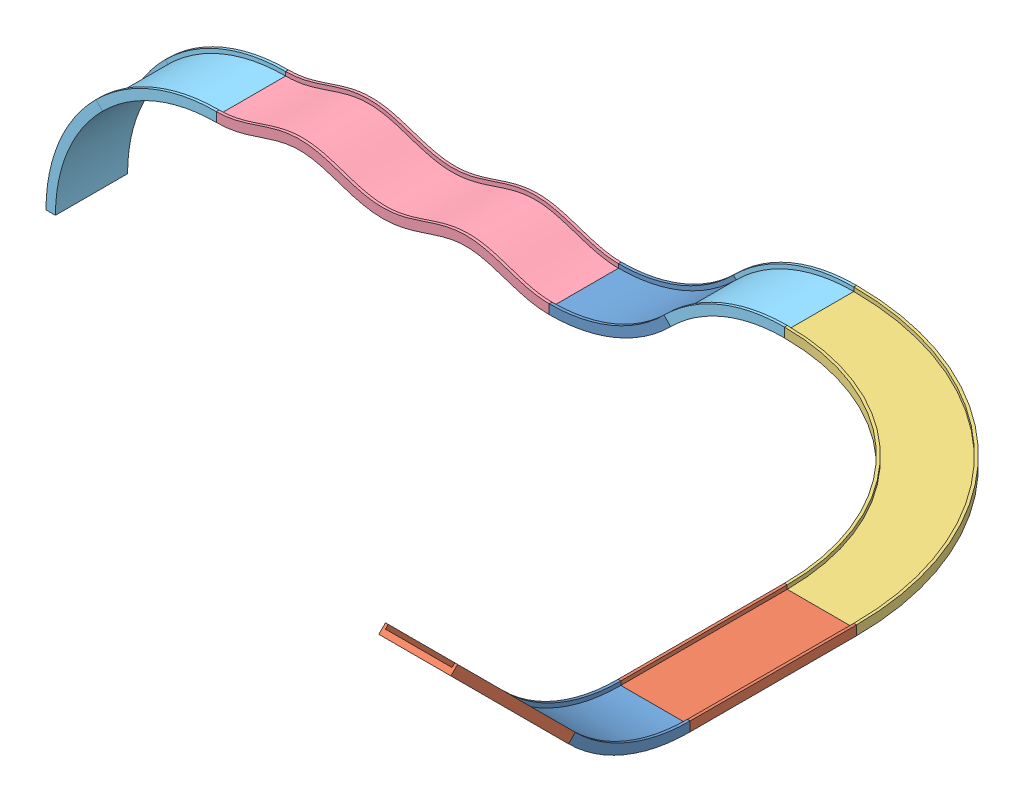
SolidWorks assembly track_js2427, configuration Default. Lengths in mm.
Overall size (9624.51 3946.21 6306.68).
9 component instances, 5 part files, 24 mates.
Components (placement in the parent):
- track_45-0_js2427-1: track_45-0_js2427 [Default] at (322.1788 1336.9708 331.0608) x (-1 0 0) z (0 0 -1) size (650 514.26 1096.02)
- track_straight_js2427-1: track_straight_js2427 [Default] at (322.1788 1336.9708 331.0608) x (-1 0 0) z (0 0 -1) size (650 85.24 1500)
- track_turn90_js2427-1: track_turn90_js2427 [Default] at (-327.8212 1336.9708 -1168.9392) size (2650 85.24 2650)
- track_waves_js2427-1: track_waves_js2427 [Default] at (-7449.1415 458.2911 -3818.9392) x (0 0 1) z (-1 0 0) size (650 244.39 3000.1)
- track_0-45_js2427-1: track_0-45_js2427 [Default] at (-8534.7174 8.6309 -3818.9392) x (0 0 1) z (-0.707107 -0.707107 0) size (650 509.93 1085.58)
- track_0-45_js2427-2: track_0-45_js2427 [Default] at (-7449.1415 458.2911 -3818.9392) x (0 0 1) z (-1 0 0) size (650 509.93 1085.58)
- track_straight_js2427-2: track_straight_js2427 [Default] at (-327.8212 1765.9902 1366.8053) x (1 0 0) z (0 0.707107 0.707107) size (650 85.24 1500)
- track_0-45_js2427-4: track_0-45_js2427 [Default] at (-2327.8212 1336.9708 -3818.9392) x (0 0 1) z (-1 0 0) size (650 509.93 1085.58)
- track_45-0_js2427-3: track_45-0_js2427 [Default] at (-4449.1415 458.2911 -3818.9392) x (0 0 1) z (-1 0 0) size (650 514.26 1096.02)
Mates (geometry in assembly coordinates):
- Coincident4: coincident: plane of track_45-0_js2427-1 through (322.1788 1336.9708 331.0608) normal (0 0 -1); plane of track_straight_js2427-1 through (322.1788 1336.9708 331.0608) normal (0 0 1)
- Coincident5: coincident: plane of track_45-0_js2427-1 through (322.1788 1765.9902 1366.8053) normal (1 0 0); plane of track_straight_js2427-1 through (322.1788 1251.7347 -1168.9392) normal (1 0 0)
- Tangent2: tangent: cylinder of track_45-0_js2427-1 through (322.1788 2801.7347 331.0608) axis (1 0 0) radius 1500; plane of track_straight_js2427-1 through (297.1788 1301.7347 -1168.9392) normal (0 1 0)
- Coincident6: coincident: plane of track_straight_js2427-1 through (322.1788 1336.9708 -1168.9392) normal (0 0 -1); plane of track_turn90_js2427-1 through (-327.8212 1336.9708 -1168.9392) normal (0 0 1)
- Coincident7: coincident: plane of track_straight_js2427-1 through (297.1788 1301.7347 -1168.9392) normal (0 1 0); plane of track_turn90_js2427-1 through (-2327.8212 1301.7347 -3193.9392) normal (0 1 0)
- Tangent3: tangent: plane of track_straight_js2427-1 through (-302.8212 1301.7347 -1168.9392) normal (1 0 0); cylinder of track_turn90_js2427-1 through (-2327.8212 1336.9708 -1168.9392) axis (0 -1 0) radius 2025
- Coincident16: coincident: line of track_0-45_js2427-1 through (-8509.8017 -16.2848 -3793.9392) axis (0 0 1); line of track_0-45_js2427-2 through (-8509.8017 -16.2848 -3793.9392) axis (0 0 1)
- Concentric4: concentric: cylinder of track_0-45_js2427-1 through (-7449.1415 -1076.9449 -3818.9392) axis (0 0 -1) radius 1500; cylinder of track_0-45_js2427-2 through (-7449.1415 -1076.9449 -3818.9392) axis (0 0 -1) radius 1500
- Coincident17: coincident: plane of track_0-45_js2427-1 through (-8899.1415 -1076.9449 -3818.9392) normal (0 0 -1); plane of track_0-45_js2427-2 through (-8474.4464 -51.6401 -3818.9392) normal (0 0 -1)
- Coincident19: coincident: plane of track_45-0_js2427-1 through (322.1788 1765.9902 1366.8053) normal (1 0 0); plane of track_straight_js2427-2 through (322.1788 2826.6504 2427.4655) normal (1 0 0)
- Tangent7: tangent: cylinder of track_45-0_js2427-1 through (322.1788 2801.7347 331.0608) axis (1 0 0) radius 1500; plane of track_straight_js2427-2 through (-302.8212 2801.7347 2452.3812) normal (0 0.707107 -0.707107)
- Coincident20: coincident: plane of track_45-0_js2427-1 through (322.1788 1765.9902 1366.8053) normal (0 0.707107 0.707107); plane of track_straight_js2427-2 through (-327.8212 1765.9902 1366.8053) normal (0 -0.707107 -0.707107)
- Coincident21: coincident: plane of track_turn90_js2427-1 through (-2327.8212 1336.9708 -3168.9392) normal (-1 0 0); plane of track_0-45_js2427-4 through (-2327.8212 1336.9708 -3818.9392) normal (1 0 0)
- Coincident22: coincident: line of track_turn90_js2427-1 through (-2327.8212 1301.7347 -3193.9392) axis (0 0 -1); line of track_0-45_js2427-4 through (-2327.8212 1301.7347 -3793.9392) axis (0 0 1)
- Tangent8: tangent: cylinder of track_turn90_js2427-1 through (-2327.8212 1336.9708 -1168.9392) axis (0 -1 0) radius 2650; plane of track_0-45_js2427-4 through (-3353.126 827.0395 -3818.9392) normal (0 0 -1)
- Coincident23: coincident: plane of track_0-45_js2427-4 through (-3413.397 887.3106 -3818.9392) normal (-0.707107 -0.707107 0); plane of track_45-0_js2427-3 through (-3413.397 887.3106 -3818.9392) normal (0.707107 0.707107 0)
- Coincident25: coincident: plane of track_0-45_js2427-4 through (-3353.126 827.0395 -3818.9392) normal (0 0 -1); plane of track_45-0_js2427-3 through (-3413.397 887.3106 -3818.9392) normal (0 0 -1)
- Coincident26: coincident: line of track_0-45_js2427-4 through (-3388.4814 862.3949 -3793.9392) axis (0 0 1); line of track_45-0_js2427-3 through (-3388.4814 862.3949 -3793.9392) axis (0 0 1)
- Coincident27: coincident: line of track_waves_js2427-1 through (-4449.1415 423.0551 -3793.9392) axis (0 0 1); line of track_45-0_js2427-3 through (-4449.1415 423.0551 -3793.9392) axis (0 0 1)
- Coincident28: coincident: plane of track_waves_js2427-1 through (-7449.1415 373.0551 -3818.9392) normal (0 0 -1); plane of track_45-0_js2427-3 through (-3413.397 887.3106 -3818.9392) normal (0 0 -1)
- Tangent9: tangent: face of track_waves_js2427-1; cylinder of track_45-0_js2427-3 through (-4449.1415 1923.0551 -3818.9392) axis (0 0 -1) radius 1500
- Coincident29: coincident: line of track_waves_js2427-1 through (-7449.1415 423.0551 -3793.9392) axis (0 0 1); line of track_0-45_js2427-2 through (-7449.1415 423.0551 -3793.9392) axis (0 0 1)
- Coincident30: coincident: plane of track_waves_js2427-1 through (-7449.1415 373.0551 -3818.9392) normal (0 0 -1); plane of track_0-45_js2427-2 through (-8474.4464 -51.6401 -3818.9392) normal (0 0 -1)
- Coincident31: coincident: plane of track_waves_js2427-1 through (-7449.1415 458.2911 -3818.9392) normal (-1 0 0); plane of track_0-45_js2427-2 through (-7449.1415 458.2911 -3818.9392) normal (1 0 0)
